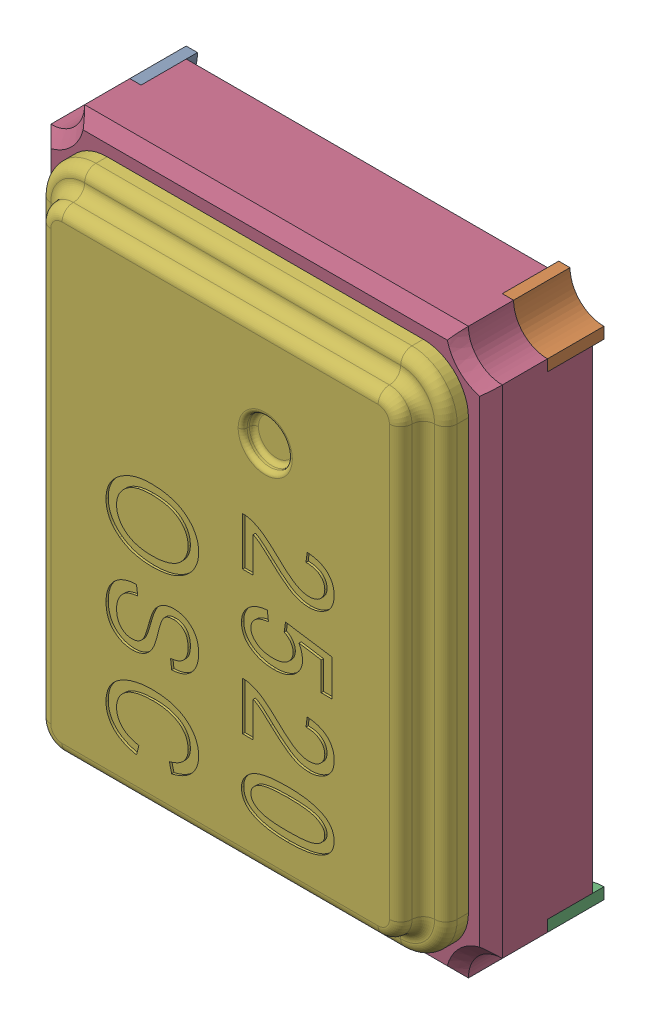
SolidWorks assembly Q7, configuration Standard. Lengths in mm.
Overall size (2 2.5 0.7).
7 component instances, 6 part files, 0 mates.
Components (placement in the parent):
- Q7-subassembly-1-1: Q7-subassembly-1 [Standard] at (-15.4 14.3 0.05) x (0 -1 0) z (-1 0 0) size (2.5 0.7 2)
  - 2520 SMD Crystal Oscillator-1: 2520 SMD Crystal Oscillator [Standard] at origin size (0.65 0.25 0.65)
  - 2520 SMD Crystal Oscillator-1-1: 2520 SMD Crystal Oscillator-1 [Standard] at origin size (0.65 0.25 0.65)
  - 2520 SMD Crystal Oscillator-2-1: 2520 SMD Crystal Oscillator-2 [Standard] at origin size (0.65 0.25 0.65)
  - 2520 SMD Crystal Oscillator-3-1: 2520 SMD Crystal Oscillator-3 [Standard] at origin size (2.5 0.45 2)
  - 2520 SMD Crystal Oscillator-4-1: 2520 SMD Crystal Oscillator-4 [Standard] at origin size (0.65 0.25 0.65)
  - 2520 SMD Crystal Oscillator-5-1: 2520 SMD Crystal Oscillator-5 [Standard] at origin size (2.3 0.2 1.8)
